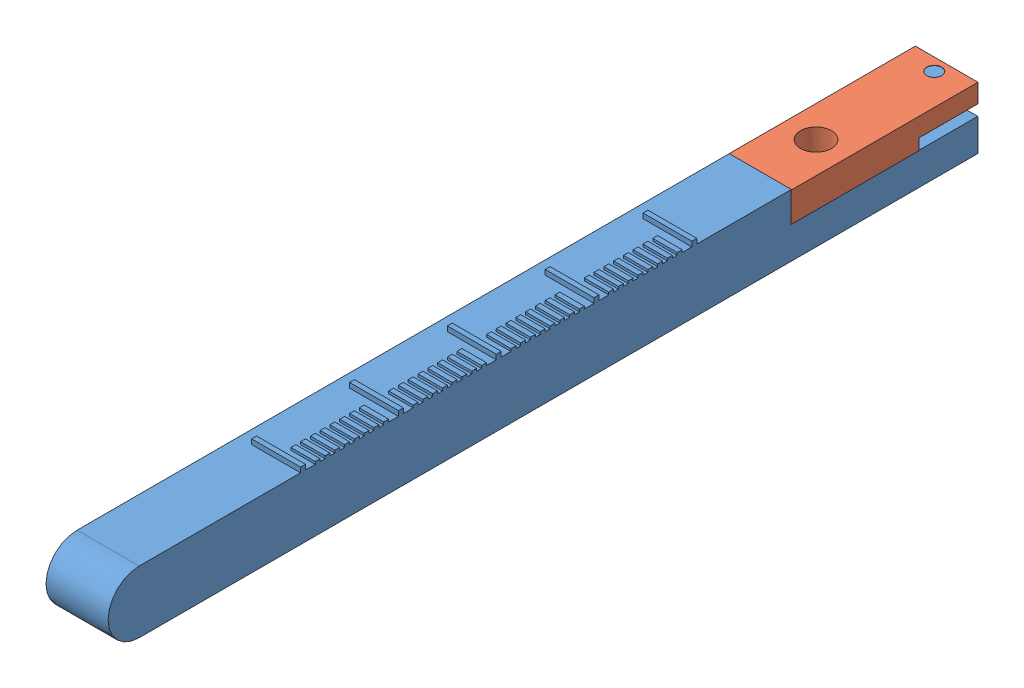
SolidWorks assembly headbar, configuration Default. Lengths in mm.
Overall size (6.4 6.86 88.9).
2 component instances, 2 part files, 1 mates.
Components (placement in the parent):
- headpost holder-1: headpost holder [Default] at (49.0764 62.9677 48.5529) x (0 1 0) z (0 0 1) size (6.86 6.35 88.9)
- headbar clamp-1: headbar clamp [Default] at (49.0764 64.2202 58.1033) x (0 0 1) z (-1 0 0) size (19.1 3.05 6.4)
Mates (geometry in assembly coordinates):
- Concentric2: concentric aligned: circle of headpost holder-1; circle of headbar clamp-1
